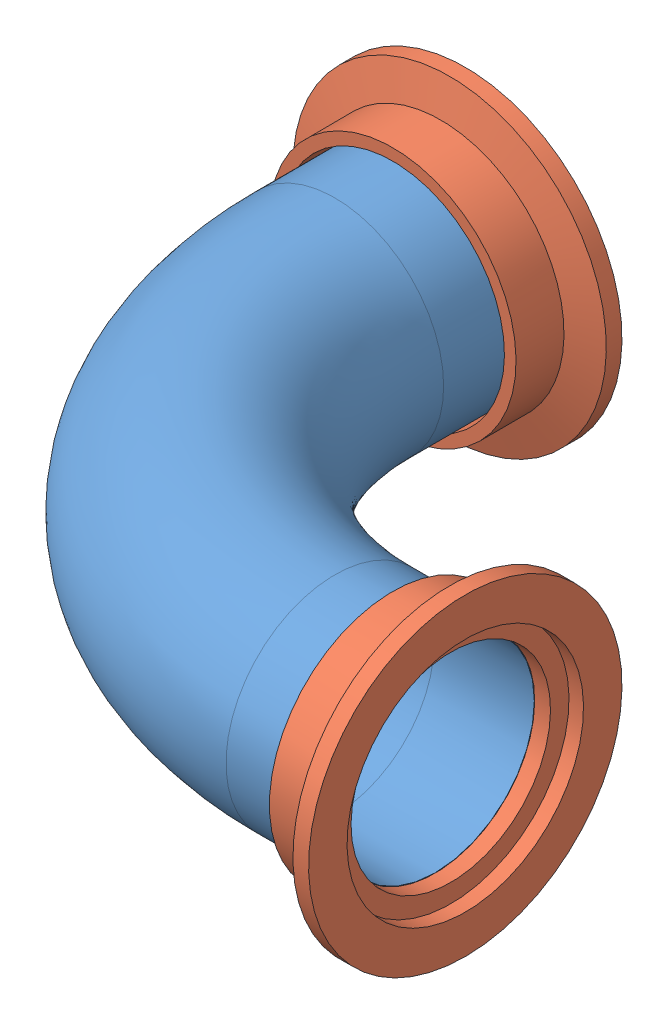
SolidWorks assembly 723020, configuration Default. Lengths in mm.
Overall size (118.59 77.21 115.37).
3 component instances, 2 part files, 4 mates.
Components (placement in the parent):
- 403542-1: 403542 [Default] at (0.8856 41.4087 23.763) size (93.73 38.1 93.73)
- 972302-1: 972302 [Default] at (0.8856 41.4087 18.4544) x (0.633478 -0.773761 0) z (0.773761 0.633478 0) size (54.86 12.7 54.86)
- 972302-2: 972302 [Default] at (80.8702 41.4087 98.439) x (0 0.355077 -0.934837) z (0 -0.934837 -0.355077) size (54.86 12.7 54.86)
Mates (geometry in assembly coordinates):
- Concentric1: concentric anti-aligned: circle of 972302-1; circle of 403542-1
- Coincident1: coincident anti-aligned: plane of 403542-1 through (0.8856 41.4087 23.763) normal (0 0 -1); plane of 972302-1 through (13.2752 26.2755 23.763) normal (0 0 1)
- Concentric2: concentric aligned: cylinder of 972302-2 through (80.8702 41.4087 98.439) axis (1 0 0) radius 21.59; circle of 403542-1
- Coincident3: coincident anti-aligned: plane of 403542-1 through (75.5616 41.4087 98.439) normal (1 0 0); plane of 972302-2 through (75.5616 48.3533 80.1554) normal (-1 0 0)
